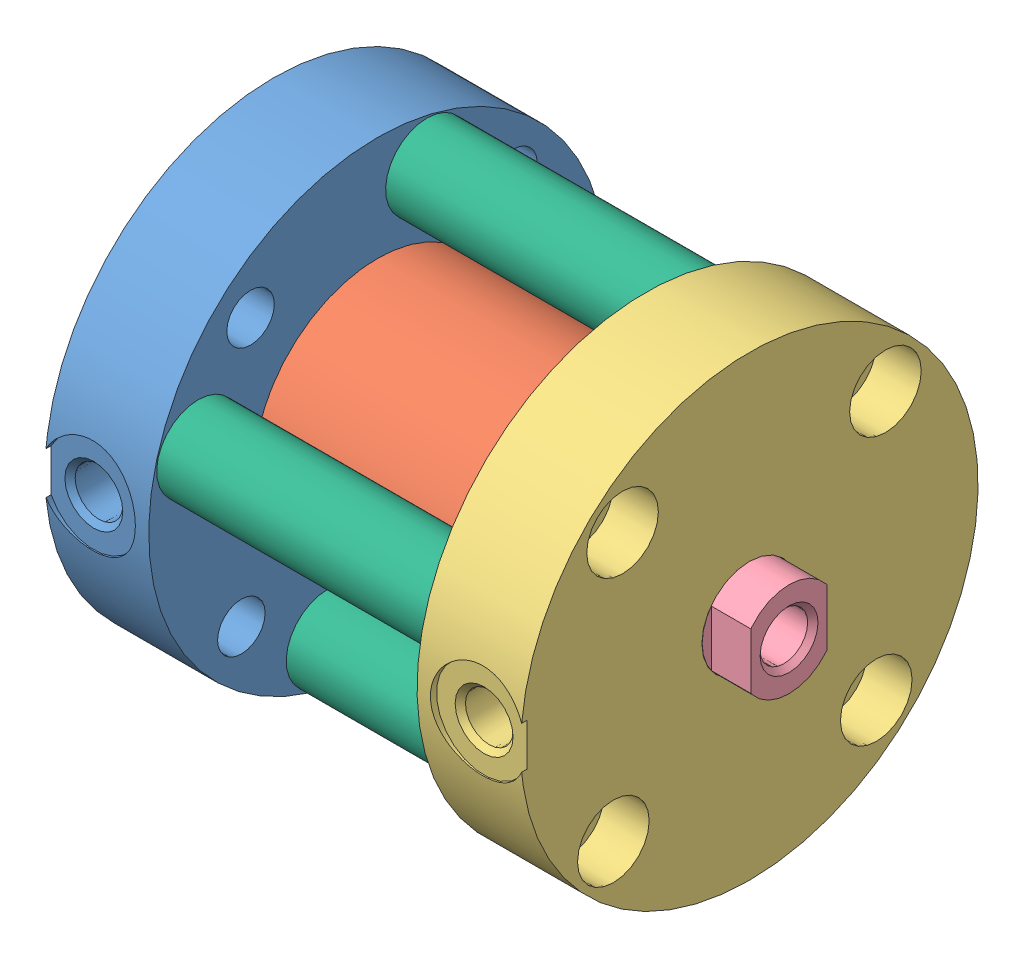
SolidWorks assembly FO-041, configuration Default. Lengths in mm.
Overall size (43.16 38.1 38.1).
9 component instances, 6 part files, 24 mates.
Components (placement in the parent):
- 04-2-0_13-FO1_BM_heads-1: 04-2-0_13-FO1_BM_heads [Default] at (8.636 0 0) x (0 0 -1) z (0 1 0) size (38.1 8.87 38.1)
- 041_22-FO1_BM_tube-1: 041_22-FO1_BM_tube [Default] at (4.318 0 0) x (0 0 -1) z (0 -1 0) size (20.62 30.99 20.62)
- 04-1-0_13-FO1_BM_heads-1: 04-1-0_13-FO1_BM_heads [Default] at (30.988 0 0) x (0 0 -1) z (0 -1 0) size (38.1 8.87 38.1)
- 041_521_52-FO1_BM_rod-1: 041_521_52-FO1_BM_rod [Default] at (4.318 0 0) x (0 0 -1) z (0 -1 0) size (7.87 38.61 7.87)
- 0_750_22-rod_part-1: 0_750_22-rod_part [Default] at (4.318 0 0) x (0 0 -1) z (-1 0 0) size (19.05 19.05 5.59)
- 041_22-FO1_BM_r-1: 041_22-FO1_BM_r [Default] at (35.306 4.1406 14.9305) x (0 0 -1) z (0 1 0) size (6.91 30.99 6.91)
- 041_22-FO1_BM_r-2: 041_22-FO1_BM_r [Default] at (35.306 14.9305 -4.1406) x (0 0 -1) z (0 1 0) size (6.91 30.99 6.91)
- 041_22-FO1_BM_r-3: 041_22-FO1_BM_r [Default] at (35.306 -4.1406 -14.9305) x (0 0 -1) z (0 1 0) size (6.91 30.99 6.91)
- 041_22-FO1_BM_r-4: 041_22-FO1_BM_r [Default] at (35.306 -14.9305 4.1406) x (0 0 -1) z (0 1 0) size (6.91 30.99 6.91)
Mates (geometry in assembly coordinates):
- Distance1: distance = 0 mm anti-aligned: plane of 041_22-FO1_BM_tube-1; plane of 04-2-0_13-FO1_BM_heads-1
- Coincident1: coincident anti-aligned: line of 04-2-0_13-FO1_BM_heads-1 through (-41.364 0 0) axis (1 0 0); line of 041_22-FO1_BM_tube-1 through (54.318 0 0) axis (-1 0 0)
- Angle3: planar angle = 0 rad aligned: plane of 041_22-FO1_BM_tube-1; plane of 04-2-0_13-FO1_BM_heads-1
- Distance3: distance = 0 mm aligned: plane of 04-1-0_13-FO1_BM_heads-1; plane of 041_22-FO1_BM_tube-1
- Coincident2: coincident aligned: line of 041_22-FO1_BM_tube-1 through (54.318 0 0) axis (-1 0 0); line of 04-1-0_13-FO1_BM_heads-1 through (80.988 0 0) axis (-1 0 0)
- Angle6: planar angle = 0 rad aligned: plane of 04-1-0_13-FO1_BM_heads-1; plane of 041_22-FO1_BM_tube-1
- LimitDistance2: limit distance = 0 mm aligned: plane of 041_521_52-FO1_BM_rod-1; plane of 04-1-0_13-FO1_BM_heads-1
- Coincident3: coincident aligned: line of 04-1-0_13-FO1_BM_heads-1 through (80.988 0 0) axis (-1 0 0); line of 041_521_52-FO1_BM_rod-1 through (54.318 0 0) axis (-1 0 0)
- Angle9: planar angle = 0 rad aligned: plane of 041_521_52-FO1_BM_rod-1; plane of 04-1-0_13-FO1_BM_heads-1
- Distance4: distance = 0 mm anti-aligned: plane of 0_750_22-rod_part-1 through (4.318 0 0) normal (-1 0 0); plane of 041_521_52-FO1_BM_rod-1
- Coincident4: coincident anti-aligned: line of 041_521_52-FO1_BM_rod-1 through (54.318 0 0) axis (-1 0 0); line of 0_750_22-rod_part-1 through (-76.582 0 0) axis (1 0 0)
- Angle12: planar angle = 0 rad aligned: plane of 0_750_22-rod_part-1; plane of 041_521_52-FO1_BM_rod-1
- Distance5: distance = 0 mm anti-aligned: plane of 041_22-FO1_BM_r-1; plane of 04-1-0_13-FO1_BM_heads-1
- Coincident5: coincident anti-aligned: line of 04-1-0_13-FO1_BM_heads-1 through (80.988 4.1406 14.9305) axis (-1 0 0); line of 041_22-FO1_BM_r-1 through (-14.694 4.1406 14.9305) axis (1 0 0)
- Angle15: planar angle = 0 rad aligned: plane of 041_22-FO1_BM_r-1; plane of 04-1-0_13-FO1_BM_heads-1
- Distance6: distance = 0 mm anti-aligned: plane of 041_22-FO1_BM_r-2; plane of 04-1-0_13-FO1_BM_heads-1
- Coincident6: coincident anti-aligned: line of 04-1-0_13-FO1_BM_heads-1 through (80.988 14.9305 -4.1406) axis (-1 0 0); line of 041_22-FO1_BM_r-2 through (-14.694 14.9305 -4.1406) axis (1 0 0)
- Angle18: planar angle = 0 rad aligned: plane of 041_22-FO1_BM_r-2; plane of 04-1-0_13-FO1_BM_heads-1
- Distance7: distance = 0 mm anti-aligned: plane of 041_22-FO1_BM_r-3; plane of 04-1-0_13-FO1_BM_heads-1
- Coincident7: coincident anti-aligned: line of 04-1-0_13-FO1_BM_heads-1 through (80.988 -4.1406 -14.9305) axis (-1 0 0); line of 041_22-FO1_BM_r-3 through (-14.694 -4.1406 -14.9305) axis (1 0 0)
- Angle21: planar angle = 0 rad aligned: plane of 041_22-FO1_BM_r-3; plane of 04-1-0_13-FO1_BM_heads-1
- Distance8: distance = 0 mm anti-aligned: plane of 041_22-FO1_BM_r-4; plane of 04-1-0_13-FO1_BM_heads-1
- Coincident8: coincident anti-aligned: line of 04-1-0_13-FO1_BM_heads-1 through (80.988 -14.9305 4.1406) axis (-1 0 0); line of 041_22-FO1_BM_r-4 through (-14.694 -14.9305 4.1406) axis (1 0 0)
- Angle24: planar angle = 0 rad aligned: plane of 041_22-FO1_BM_r-4; plane of 04-1-0_13-FO1_BM_heads-1
